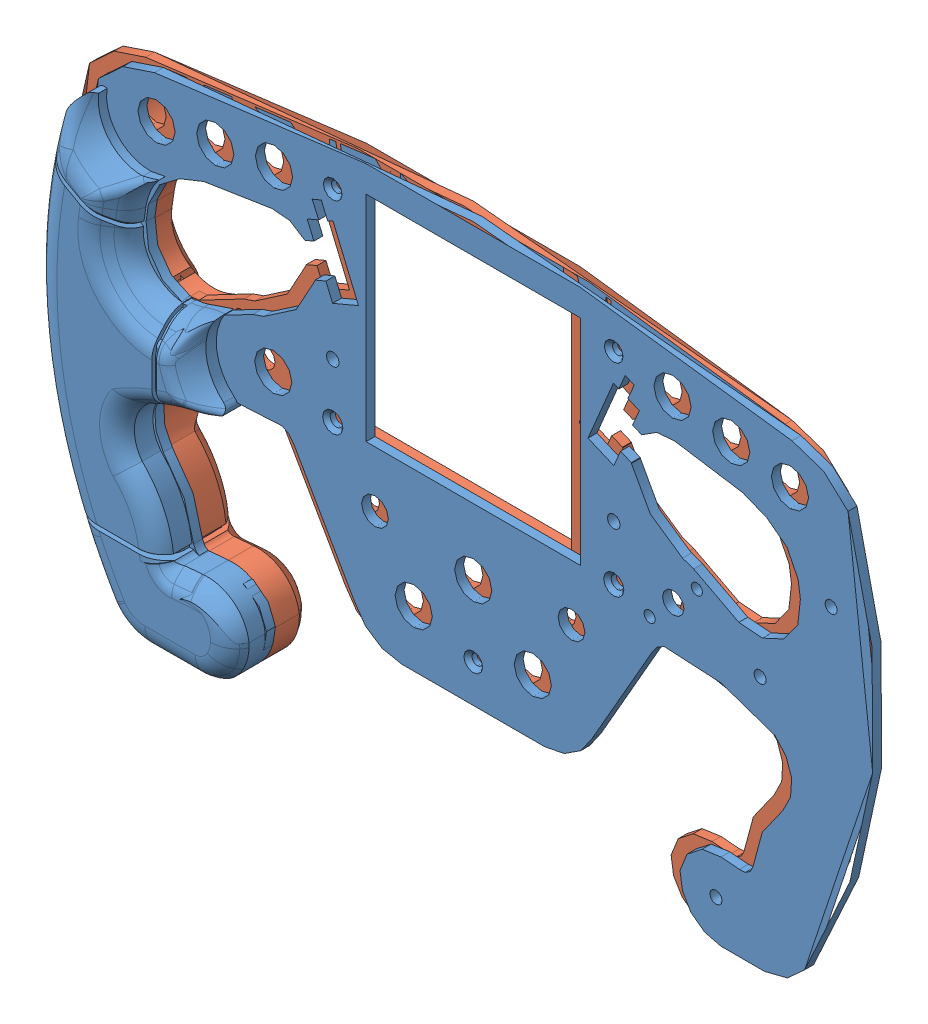
SolidWorks assembly shifter assem with bigger thumb radius, configuration Default. Lengths in mm.
Overall size (68.83 150.75 30.95).
2 component instances, 2 part files, 3 mates.
Components (placement in the parent):
- left grip narrow-1: left grip narrow [Default] at (134.9657 135.7489 199.5991) size (273.72 171.6 15)
- left grip back narrow-1: left grip back narrow [Default] at (134.9657 135.7489 199.5991) x (-1 0 0) z (0 0 -1) size (270.09 171.6 15.95)
Mates (geometry in assembly coordinates):
- Concentric1: concentric: circle of left grip narrow-1; circle of left grip back narrow-1
- Coincident2: coincident anti-aligned: plane of left grip narrow-1 through (134.9657 135.7489 199.5991) normal (0 0 -1); plane of left grip back narrow-1 through (134.9657 135.7489 199.5991) normal (0 0 1)
- Coincident3: coincident: point of left grip narrow-1; point of left grip back narrow-1
